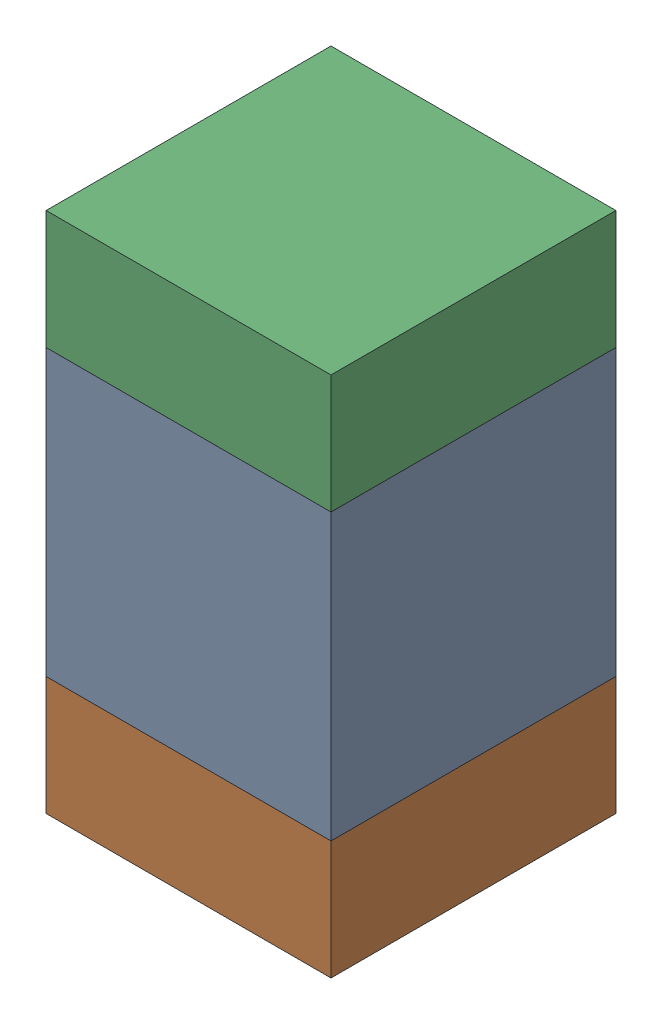
SolidWorks assembly C310_2PCB, configuration Default. Lengths in mm.
Overall size (0.6 1.1 0.6).
6 component instances, 2 part files, 0 mates.
Components (placement in the parent):
- 761606048-1: 761606048 [Default] at (144.4 91.1 0) size (0.6 0.6 0.6)
  - Extruded_9-1: Extruded_9 [Default] at origin size (0.6 0.6 0.6)
- 854785296-1: 854785296 [Default] at (144.4 90.675 0) size (0.6 0.25 0.6)
  - Extruded_10-1: Extruded_10 [Default] at origin size (0.6 0.25 0.6)
- 854785296-2: 854785296 [Default] at (144.4 91.525 0) size (0.6 0.25 0.6)
  - Extruded_10-1: Extruded_10 [Default] at origin size (0.6 0.25 0.6)
